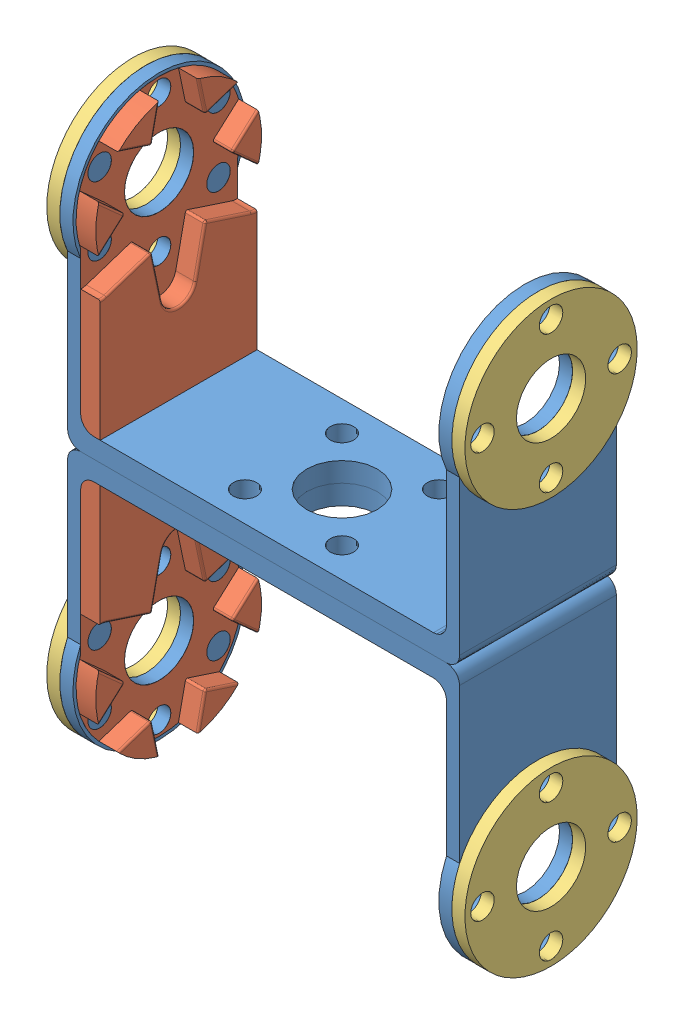
SolidWorks assembly box3_supplement_horn, configuration Predeterminado. Lengths in mm.
Overall size (64 88.44 26.36).
8 component instances, 3 part files, 23 mates.
Components (placement in the parent):
- u_bracket-1: u_bracket [Predeterminado] at (0 0 -0.0751) size (60 44.22 26.36)
- u_bracket-2: u_bracket [Predeterminado] at (0 -2 -0.0751) x (-1 0 0) z (0 0 1) size (60 44.22 26.36)
- supplement_u_f_horn-1: supplement_u_f_horn [Predeterminado] at (-28 30.04 -0.0751) x (0 1 0) z (0 0 -1) size (40.74 3.02 25.4)
- supplement_u_f_horn-3: supplement_u_f_horn [Predeterminado] at (-28 -32.04 -0.0751) x (0 -1 0) z (0 0 1) size (40.74 3.02 25.4)
- suplement_external_bracket-1: suplement_external_bracket [Predeterminado] at (-32 30.04 -0.0751) x (0 0 1) z (0 1 0) size (26.36 2 26.36)
- suplement_external_bracket-2: suplement_external_bracket [Predeterminado] at (-32 -32.04 -0.0751) x (0 0 1) z (0 1 0) size (26.36 2 26.36)
- suplement_external_bracket-3: suplement_external_bracket [Predeterminado] at (30 -32.04 -0.0751) x (0 -1 0) z (0 0 1) size (26.36 2 26.36)
- suplement_external_bracket-4: suplement_external_bracket [Predeterminado] at (30 30.04 -0.0751) x (0 -1 0) z (0 0 1) size (26.36 2 26.36)
Mates (geometry in assembly coordinates):
- Coincidente1: coincident anti-aligned: plane of u_bracket-1 through (0 -1 -6.2726) normal (0 -1 0); plane of u_bracket-2 through (0 -1 -6.2726) normal (0 1 0)
- Concéntrica1: concentric anti-aligned: circle of u_bracket-1; circle of u_bracket-2
- Coincidente3: coincident aligned: plane of u_bracket-1 through (-30 2 5.7274) normal (0 0 1); plane of u_bracket-2 through (30 -4 5.7274) normal (0 0 1)
- Coincidente5: coincident anti-aligned: plane of u_bracket-1 through (-28 30.04 -6.2726) normal (1 0 0); plane of supplement_u_f_horn-1 through (-28 30.04 -6.2726) normal (-1 0 0)
- Concéntrica6: concentric aligned: circle of u_bracket-1; circle of supplement_u_f_horn-1
- Coincidente6: coincident aligned: plane of u_bracket-1 through (-30 2 -18.2726) normal (0 0 -1); plane of supplement_u_f_horn-1 through (-25 2 -18.2726) normal (0 0 -1)
- Coincidente7: coincident anti-aligned: plane of u_bracket-2 through (-28 -32.04 -6.2726) normal (1 0 0); plane of supplement_u_f_horn-3 through (-28 -32.04 -6.2726) normal (-1 0 0)
- Coincidente8: coincident anti-aligned: cylinder of u_bracket-2 through (-28 -32.04 -6.2726) axis (-1 0 0) radius 5.3; circle of supplement_u_f_horn-3
- Coincidente10: coincident aligned: plane of u_bracket-2 through (30 -4 -18.2726) normal (0 0 -1); plane of supplement_u_f_horn-3 through (-25 -4 -18.2726) normal (0 0 -1)
- Concéntrica7: concentric aligned: cylinder of u_bracket-1 through (-28 30.04 -6.2726) axis (-1 0 0) radius 5.3; cylinder of suplement_external_bracket-1 through (-30 30.04 -6.2726) axis (-1 0 0) radius 5.3
- Concéntrica8: concentric anti-aligned: cylinder of u_bracket-1 through (30.001 40.54 -6.2726) axis (-1 0 0) radius 1.8; cylinder of suplement_external_bracket-1 through (-32 40.54 -6.2726) axis (1 0 0) radius 1.8
- Coincidente11: coincident anti-aligned: plane of u_bracket-1 through (-30 2 -18.2726) normal (-1 0 0); plane of suplement_external_bracket-1 through (-30 30.04 -6.2726) normal (1 0 0)
- Concéntrica9: concentric aligned: cylinder of u_bracket-2 through (-28 -32.04 -6.2726) axis (-1 0 0) radius 5.3; cylinder of suplement_external_bracket-2 through (-30 -32.04 -6.2726) axis (-1 0 0) radius 5.3
- Concéntrica10: concentric anti-aligned: cylinder of u_bracket-2 through (30.001 -21.54 -6.2726) axis (-1 0 0) radius 1.8; cylinder of suplement_external_bracket-2 through (-32 -21.54 -6.2726) axis (1 0 0) radius 1.8
- Coincidente12: coincident anti-aligned: plane of u_bracket-2 through (-30 -4 -18.2726) normal (-1 0 0); plane of suplement_external_bracket-2 through (-30 -32.04 -6.2726) normal (1 0 0)
- Coincidente13: coincident aligned: plane of u_bracket-1 through (0 0 -6.2726) normal (0 1 0); plane of assembly through (0 0 0) normal (0 1 0)
- Coincidente14: coincident aligned: plane of u_bracket-1 through (0 0 -6.2726) normal (1 0 0); plane of assembly through (0 0 0) normal (1 0 0)
- Concéntrica11: concentric: cylinder of u_bracket-2 through (28 -32.04 -0.0751) axis (1 0 0) radius 5.3; cylinder of suplement_external_bracket-3 through (32 -32.04 -0.0751) axis (-1 0 0) radius 5.3
- Concéntrica12: concentric: cylinder of u_bracket-2 through (-30.001 -42.54 -0.0751) axis (1 0 0) radius 1.8; cylinder of suplement_external_bracket-3 through (30 -42.54 -0.0751) axis (1 0 0) radius 1.8
- Coincidente16: coincident anti-aligned: plane of u_bracket-2 through (30 -4 -12.0751) normal (1 0 0); plane of suplement_external_bracket-3 through (30 -32.04 -0.0751) normal (-1 0 0)
- Concéntrica13: concentric: cylinder of u_bracket-1 through (28 30.04 -0.0751) axis (1 0 0) radius 5.3; cylinder of suplement_external_bracket-4 through (32 30.04 -0.0751) axis (-1 0 0) radius 5.3
- Concéntrica14: concentric: cylinder of u_bracket-1 through (-30.001 40.54 -0.0751) axis (1 0 0) radius 1.8; cylinder of suplement_external_bracket-4 through (30 40.54 -0.0751) axis (1 0 0) radius 1.8
- Coincidente17: coincident anti-aligned: plane of u_bracket-1 through (30 2 -12.0751) normal (1 0 0); plane of suplement_external_bracket-4 through (30 30.04 -0.0751) normal (-1 0 0)
